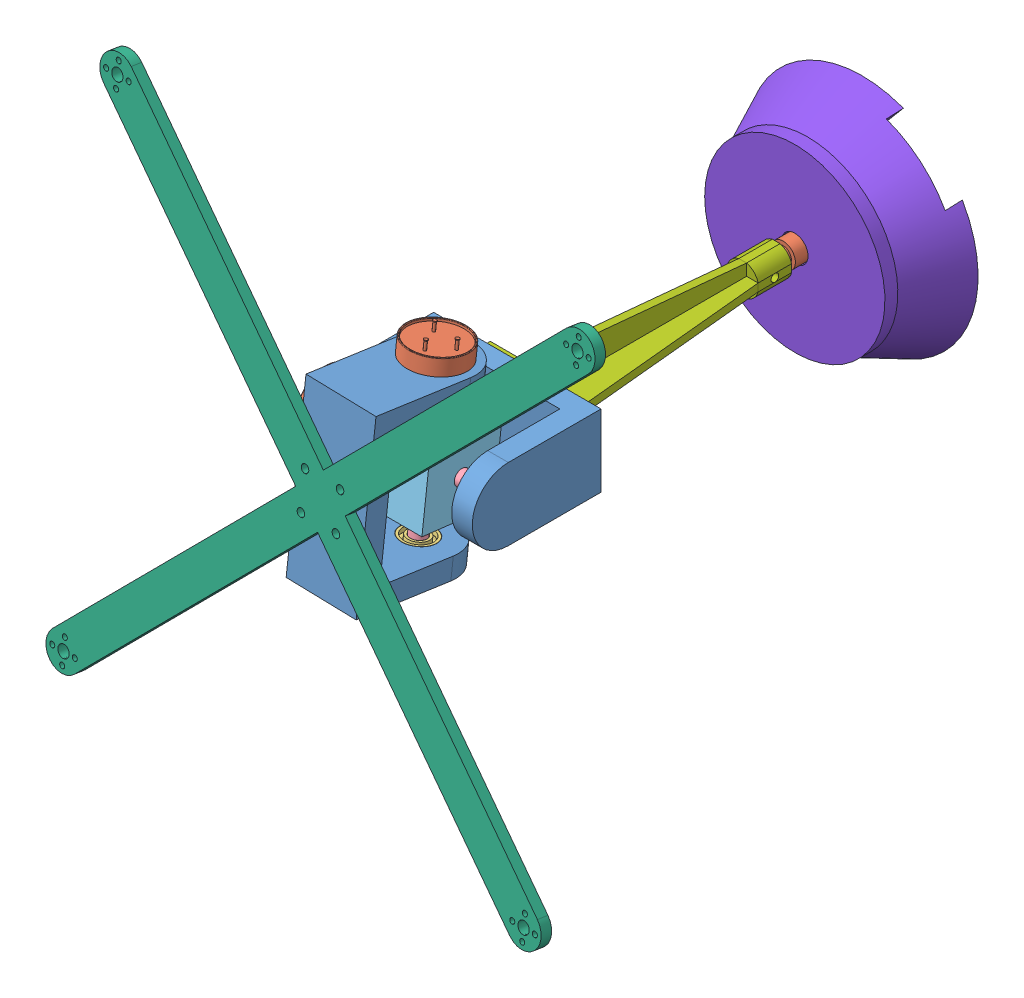
SolidWorks assembly Plataforma, configuration Predeterminado. Lengths in mm.
Overall size (198.85 198.56 223.66).
13 component instances, 8 part files, 26 mates.
Components (placement in the parent):
- Soporte-1: Soporte [Predeterminado] at (-37.3355 -16.5904 40) size (65 28 50)
- Sensor_BI6127-1: Sensor_BI6127 [Default] at (-43.3855 -2.5904 76) x (0 -1 0) z (0 0 1) size (22.23 35.88 22.23)
- Rodamiento-1: Rodamiento [Predeterminado] at (22.1645 -2.5904 76) size (5 13 13)
- Eje-1: Eje [Predeterminado] at (-0.3355 -2.5904 76) size (25 6 6)
- BloqueCentral-1: BloqueCentral [Predeterminado] at (-18.3355 9.6518 60.4395) x (1 0 0) z (0 -0.992953 0.118508) size (28 28 28)
- Soporte-2: Soporte [Predeterminado] at (8.6229 33.4963 108.3392) x (0 -0.992953 0.118508) z (0.028772 -0.118459 -0.992542) size (65 28 50)
- Rodamiento-2: Rodamiento [Predeterminado] at (-4.3355 -29.8966 79.259) x (0 -0.992953 0.118508) z (0.561246 -0.098083 -0.821817) size (5 13 13)
- Eje-2: Eje [Predeterminado] at (-4.3355 -7.5552 76.5925) x (0 -0.992953 0.118508) z (0.561246 -0.098083 -0.821817) size (25 6 6)
- Sensor_BI6127-2: Sensor_BI6127 [Default] at (-4.3355 35.1914 71.4908) x (0.826728 0.066673 0.558637) z (0.562602 -0.097974 -0.820902) size (22.23 35.88 22.23)
- Frame-1: Frame [Predeterminado] at (-19.3311 -12.8053 113.0549) x (0.999574 0.008268 0.027989) z (-0.028772 0.118459 0.992542) size (197.85 197.85 4)
- SoporteVertical-1: SoporteVertical [Predeterminado] at (-37.3355 -16.5904 40) x (-1 0 0) z (0 0 -1) size (28 27.8 100)
- Sensor_BI6127-3: Sensor_BI6127 [Default] at (-4.3355 -4.2495 -83.28) x (0.925122 -0.37967 0) z (-0.37967 -0.925122 0) size (22.23 35.88 22.23)
- BloqueBase-1: BloqueBase [Predeterminado] at (-4.3355 -4.2495 -55.3481) x (0.762866 -0.646557 0) z (-0.646557 -0.762866 0) size (90 26.16 87.64)
Mates (geometry in assembly coordinates):
- Coincidente1: coincident anti-aligned: plane of Soporte-1 through (-32.3355 -2.5904 76) normal (-1 0 0); plane of Sensor_BI6127-1 through (-32.3355 -2.5904 76) normal (1 0 0)
- Concéntrica1: concentric anti-aligned: circle of Soporte-1; circle of Sensor_BI6127-1
- Coincidente2: coincident anti-aligned: plane of Soporte-1 through (24.6645 -2.5904 76) normal (-1 0 0); plane of Rodamiento-1 through (24.6645 3.7596 76) normal (1 0 0)
- Concéntrica2: concentric aligned: circle of Soporte-1; circle of Rodamiento-1
- Coincidente3: coincident anti-aligned: plane of Soporte-1 through (24.6645 -2.5904 76) normal (-1 0 0); plane of Eje-1 through (24.6645 -2.5904 76) normal (1 0 0)
- Concéntrica3: concentric aligned: circle of Rodamiento-1; circle of Eje-1
- Concéntrica5: concentric aligned: circle of Eje-1; circle of BloqueCentral-1
- Distancia2: distance = 10 mm anti-aligned: plane of BloqueCentral-1 through (9.6645 -18.1509 63.7578) normal (1 0 0); plane of Soporte-1 through (19.6645 -16.5904 76) normal (-1 0 0)
- Coincidente10: coincident anti-aligned: plane of Soporte-2 through (-4.3355 -32.379 79.5552) normal (0 0.992953 -0.118508); plane of Rodamiento-2 through (-9.591 -32.8014 76.0164) normal (0 -0.992953 0.118508)
- Concéntrica6: concentric aligned: circle of Soporte-2; circle of Rodamiento-2
- Coincidente11: coincident anti-aligned: plane of Soporte-2 through (-4.3355 -32.379 79.5552) normal (0 0.992953 -0.118508); plane of Eje-2 through (-4.3355 -32.379 79.5552) normal (0 -0.992953 0.118508)
- Concéntrica7: concentric aligned: circle of Rodamiento-2; circle of Eje-2
- Coincidente12: coincident anti-aligned: plane of Soporte-2 through (-4.3355 24.2193 72.8003) normal (0 0.992953 -0.118508); plane of Sensor_BI6127-2 through (-4.3355 24.2193 72.8003) normal (0 -0.992953 0.118508)
- Concéntrica8: concentric anti-aligned: circle of Soporte-2; circle of Sensor_BI6127-2
- Concéntrica9: concentric aligned: circle of BloqueCentral-1; circle of Eje-2
- Distancia3: distance = 10 mm anti-aligned: plane of BloqueCentral-1 through (-18.3355 9.6518 60.4395) normal (0 0.992953 -0.118508); plane of Soporte-2 through (9.6587 21.2882 73.5558) normal (0 -0.992953 0.118508)
- Coincidente13: coincident anti-aligned: plane of Soporte-2 through (8.6229 33.4963 108.3392) normal (-0.028772 0.118459 0.992542); plane of Frame-1 through (-19.3311 -12.8053 113.0549) normal (0.028772 -0.118459 -0.992542)
- Concéntrica10: concentric anti-aligned: circle of Soporte-2; circle of Frame-1
- EnPosición1: in place: plane of Soporte-1 through (-37.3355 -16.5904 40) normal (0 0 -1); plane of ? through (0 0 40) normal (0 0 -1); moOrthogonalPlaneRef_w of Soporte-1 through (-37.3355 -16.5904 40) normal (0 0 -1); plane of ? through (0 0 40) normal (0 1 0); plane of Soporte-1 through (-37.3355 -16.5904 40) normal (0 0 -1); plane of ? through (0 0 40) normal (-1 0 0); plane of Soporte-1 through (-37.3355 -16.5904 40) normal (0 0 -1); unknown of SoporteVertical-1
- Coincidente14: coincident aligned: plane of Soporte-1; plane of SoporteVertical-1
- Coincidente15: coincident aligned: moOrthogonalPlaneRef_w of Soporte-1 through (-37.3355 -16.5904 40) normal (0 1 0); plane of Pieza1^Plataforma-1 through (-37.3355 -16.5904 40) normal (0 1 0)
- Coincidente16: coincident anti-aligned: moOrthogonalPlaneRef_w of Soporte-1 through (-37.3355 -16.5904 40) normal (1 0 0); plane of Pieza1^Plataforma-1 through (-37.3355 -16.5904 40) normal (-1 0 0)
- Coincidente18: coincident anti-aligned: plane of SoporteVertical-1 through (-4.3355 -4.2495 -50) normal (0 0 -1); plane of Sensor_BI6127-3 through (-4.3355 -4.2495 -50) normal (0 0 1)
- Concéntrica12: concentric anti-aligned: circle of SoporteVertical^Plataforma-1; circle of Sensor_BI6127-3
- Coincidente19: coincident anti-aligned: plane of Sensor_BI6127-3 through (-4.3355 -4.2495 -72.23) normal (0 0 1); plane of BloqueBase-1 through (-4.3355 -4.2495 -72.23) normal (0 0 -1)
- Concéntrica13: concentric aligned: circle of Sensor_BI6127-3; circle of BloqueBase-1
